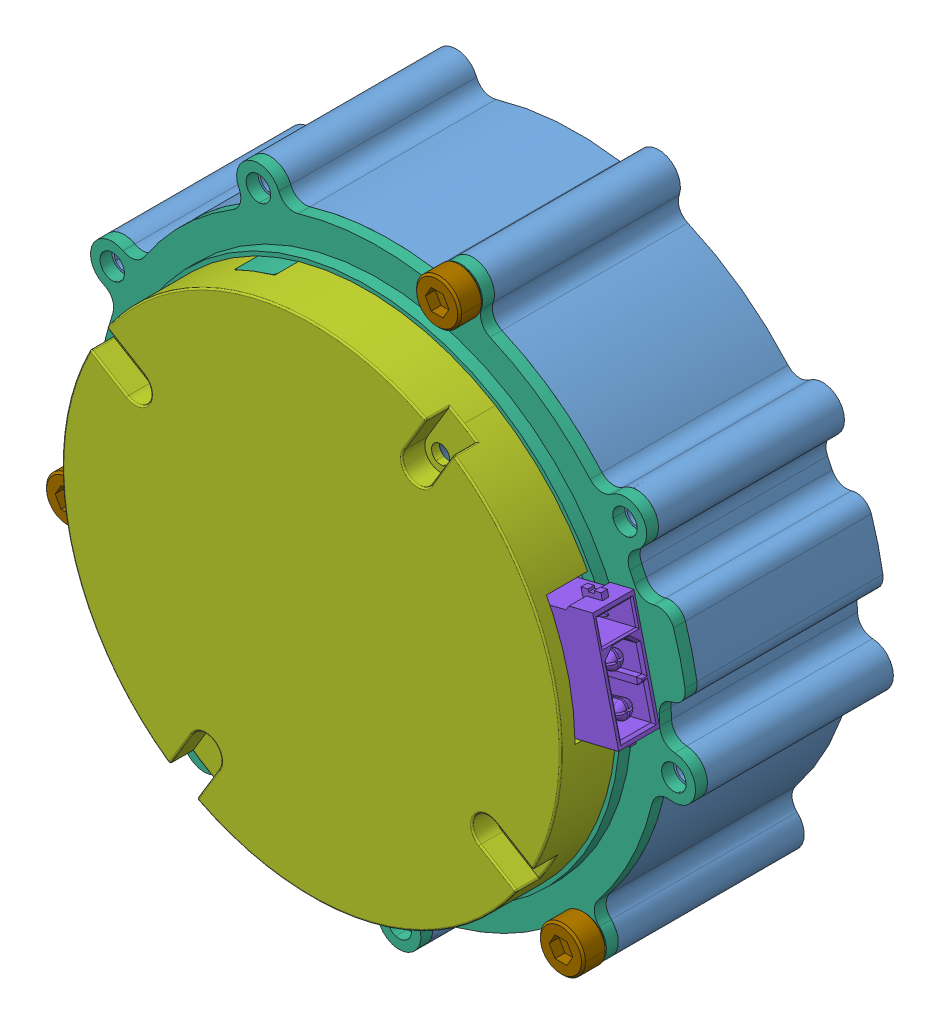
SolidWorks assembly CyberGearmotor.stp, configuration 默认. Lengths in mm.
Overall size (96.28 96.17 36.5).
19 component instances, 10 part files, 0 mates.
Components (placement in the parent):
- ASM0002_ASM_1_ASM.stp-1: ASM0002_ASM_1_ASM.stp [默认] at origin size (96.28 96.17 36.5)
  - ASM0002_ASM_1_ASM_1_ASM.stp-1: ASM0002_ASM_1_ASM_1_ASM.stp [默认] at origin size (96.28 96.17 36.5)
    - 0714_ASM_1_ASM_1_ASM_1_ASM.stp-1: 0714_ASM_1_ASM_1_ASM_1_ASM.stp [默认] at origin size (96.28 96.17 36.5)
      - 3_1_02_067_0003_ASM_ASM_1_ASM_1_ASM.stp-1: 3_1_02_067_0003_ASM_ASM_1_ASM_1_ASM.stp [默认] at origin size (96.28 96.17 36.5)
        - 3_1_02_067_0003_ASM_1_ASM_1_ASM_ASM.stp-1: 3_1_02_067_0003_ASM_1_ASM_1_ASM_ASM.stp [默认] at origin size (96.28 96.17 36.5)
          - 1_1_06_EB673-504_1_1_1_1_1.stp-1: 1_1_06_EB673-504_1_1_1_1_1.stp [默认] at (39.8324 39.833 -22) size (79.19 78.95 25.5)
          - 1_2_04_670601_1_1_1_1_1.stp-1: 1_2_04_670601_1_1_1_1_1.stp [默认] at (93.9161 79.9966 -44) size (37 37 4)
          - 1_1_02_EB671-500_1_1_1_1_1.stp-1: 1_1_02_EB671-500_1_1_1_1_1.stp [默认] at (93.9161 79.9966 -44.4) x (-0.960973 0.276644 0) z (0 0 1) size (33 33 8.5)
          - 1_2_04_694000_1_1_1_1_1.stp-1: 1_2_04_694000_1_1_1_1_1.stp [默认] at (93.9161 79.9966 -44.5) size (11 11 4)
          - 1_2_06_000213_1_1_1_1_1.stp-1: 1_2_06_000213_1_1_1_1_1.stp [默认] at (93.9161 79.9966 -45.5) size (38.8 36.2 1.5)
          - 1_1_31_QT-642_1_1_1_1_1.stp-1: 1_1_31_QT-642_1_1_1_1_1.stp [默认] at (93.9161 79.9966 -22) x (-0.970555 -0.24088 0) z (0 0 -1) size (79.5 79.36 6)
          - 1_1_06_EB673-502_1_1_1_1_1.stp-1: 1_1_06_EB673-502_1_1_1_1_1.stp [默认] at (93.9161 79.9966 -13) x (-0.515958 -0.856614 0) z (0 0 -1) size (63 63 8)
        - 0518_ASM_2_ASM_1_ASM_1_ASM_1_AS_ASM.stp-1: 0518_ASM_2_ASM_1_ASM_1_ASM_1_AS_ASM.stp [默认] at (93.9161 79.9966 -17.235) x (0.235897 -0.971778 0) z (0 0 1) size (15.5 11.3 5.2)
          - 12345_ASM_1_ASM_2_ASM_1_ASM_1_A_ASM.stp-1: 12345_ASM_1_ASM_2_ASM_1_ASM_1_A_ASM.stp [默认] at origin size (15.5 11.3 5.2)
            - DUANZI_1_3_1_1_1_1_1_1.stp-1: DUANZI_1_3_1_1_1_1_1_1.stp [默认] at (-0.1798 16.5474 0.4329) x (0 0 -1) z (0 1 0) size (5.2 15.5 11.3)
    - LUODING_1_1.stp-1: LUODING_1_1.stp [默认] at (119.9375 52.9941 -20.5) x (-1 0 0) z (0 1 0) size (5.68 3 5.68)
    - LUODING_1_1.stp-2: LUODING_1_1.stp [默认] at (104.2902 116.0331 -20.5) x (-1 0 0) z (0 1 0) size (5.68 3 5.68)
    - LUODING_1_1.stp-3: LUODING_1_1.stp [默认] at (57.5205 70.9626 -20.5) x (-1 0 0) z (0 1 0) size (5.68 3 5.68)
- 0411-2_4_1_3_1.stp-1: 0411-2_4_1_3_1.stp [默认] at (93.9161 79.9964 -17.5) x (0.235904 -0.971776 0) z (0 0 1) size (58 56.68 1.62)
